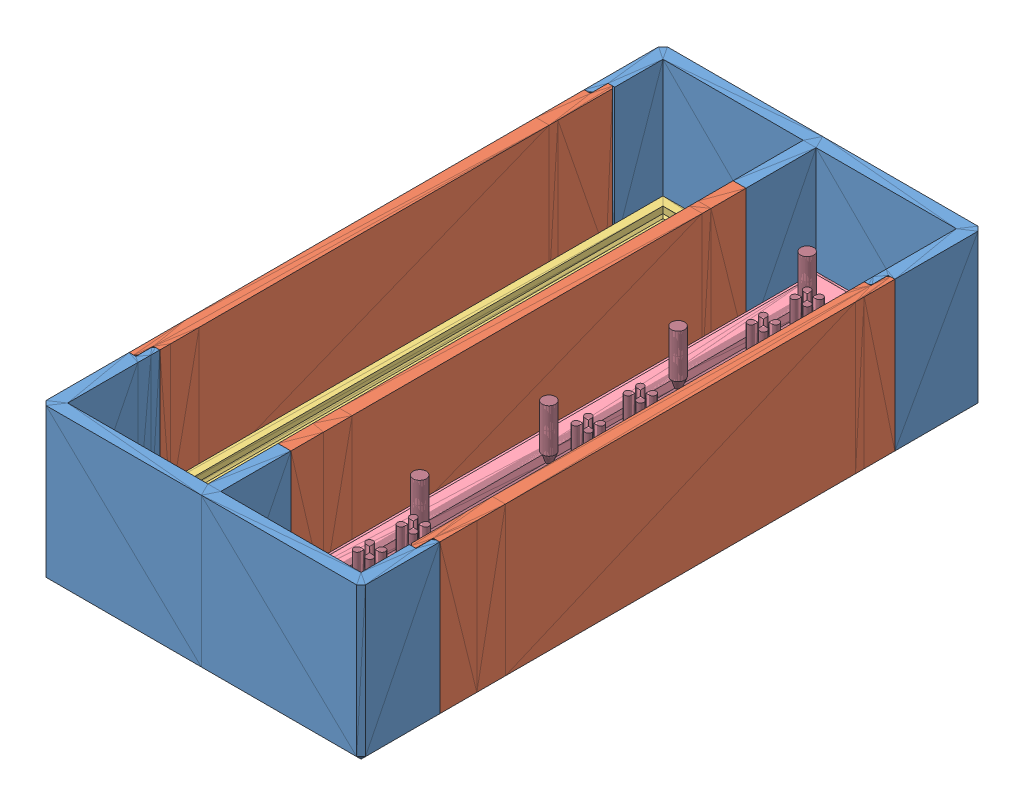
SolidWorks assembly Assem2, configuration Default. Lengths in mm.
Overall size (73.01 35 142).
5 component instances, 4 part files, 12 mates.
Components (placement in the parent):
- 1U-No-Hassle-1: 1U-No-Hassle [Default] at (-53.4862 -8.8449 7) size (73 35 24)
- noHassle-SpacebarExtend1-1: noHassle-SpacebarExtend1 [Default] at (-53.4875 -8.8449 -240) size (73.01 35 114)
- 1U-No-Hassle-2: 1U-No-Hassle [Default] at (-18.4862 -8.8449 111) x (-1 0 0) z (0 0 -1) size (73 35 24)
- ZButt-MasterBase-6.25u-1: ZButt-MasterBase-6.25u [Default] at (-85.4737 -3.8449 -399.975) x (0 0 1) z (0 1 0) size (136 32 9)
- ZButt-StemCavity-6.25u-Sprue-1: ZButt-StemCavity-6.25u-Sprue [Default] at (-50.5081 -1.3449 14.025) x (0 0 1) z (0 1 0) size (136 32 19.5)
Mates (geometry in assembly coordinates):
- Coincident1: coincident aligned: plane of 1U-No-Hassle-1 through (-53.4862 -11.8449 7) normal (0 -1 0); plane of noHassle-SpacebarExtend1-1 through (-53.4875 -11.8449 -240) normal (0 -1 0)
- Coincident2: coincident aligned: plane of 1U-No-Hassle-1 through (0.5138 -8.8449 7) normal (1 0 0); plane of noHassle-SpacebarExtend1-1 through (0.5138 -8.8449 -240) normal (1 0 0)
- Coincident3: coincident: plane of 1U-No-Hassle-1 through (-53.4862 -8.8449 10) normal (0 0 1); point of noHassle-SpacebarExtend1-1
- Coincident4: coincident anti-aligned: plane of noHassle-SpacebarExtend1-1 through (-53.4875 -8.8449 110) normal (0 0 1); plane of 1U-No-Hassle-2 through (-18.4862 -8.8449 110) normal (0 0 -1)
- Coincident5: coincident aligned: plane of noHassle-SpacebarExtend1-1 through (0.5138 -8.8449 -240) normal (1 0 0); plane of 1U-No-Hassle-2 through (0.5138 -8.8449 111) normal (1 0 0)
- Coincident6: coincident aligned: plane of noHassle-SpacebarExtend1-1 through (-53.4875 23.1551 -240) normal (0 1 0); plane of 1U-No-Hassle-2 through (-18.4862 23.1551 111) normal (0 1 0)
- Coincident7: coincident: plane of noHassle-SpacebarExtend1-1 through (-53.4875 -8.8449 -240) normal (0 1 0); plane of ZButt-MasterBase-6.25u-1 through (-85.4737 -8.8449 -399.975) normal (0 -1 0)
- Coincident8: coincident: plane of noHassle-SpacebarExtend1-1 through (-69.4737 -8.8449 -240) normal (1 0 0); plane of ZButt-MasterBase-6.25u-1 through (-69.4737 -3.8449 -399.975) normal (-1 0 0)
- Coincident9: coincident anti-aligned: plane of 1U-No-Hassle-2 through (-18.4862 -8.8449 127.025) normal (0 0 -1); plane of ZButt-MasterBase-6.25u-1 through (-85.4737 -3.8449 127.025) normal (0 0 1)
- Coincident10: coincident: plane of noHassle-SpacebarExtend1-1 through (-53.4875 -8.8449 -240) normal (0 1 0); plane of ZButt-StemCavity-6.25u-Sprue-1 through (-49.0038 -6.2359 53.7332) normal (0 -1 0)
- Coincident11: coincident: plane of noHassle-SpacebarExtend1-1 through (-34.5081 -8.8449 -240) normal (1 0 0); plane of ZButt-StemCavity-6.25u-Sprue-1 through (-34.5081 -1.3449 14.025) normal (-1 0 0)
- Coincident12: coincident anti-aligned: plane of 1U-No-Hassle-2 through (-18.4862 -8.8449 127.025) normal (0 0 -1); plane of ZButt-StemCavity-6.25u-Sprue-1 through (-50.5081 -1.3449 127.025) normal (0 0 1)
